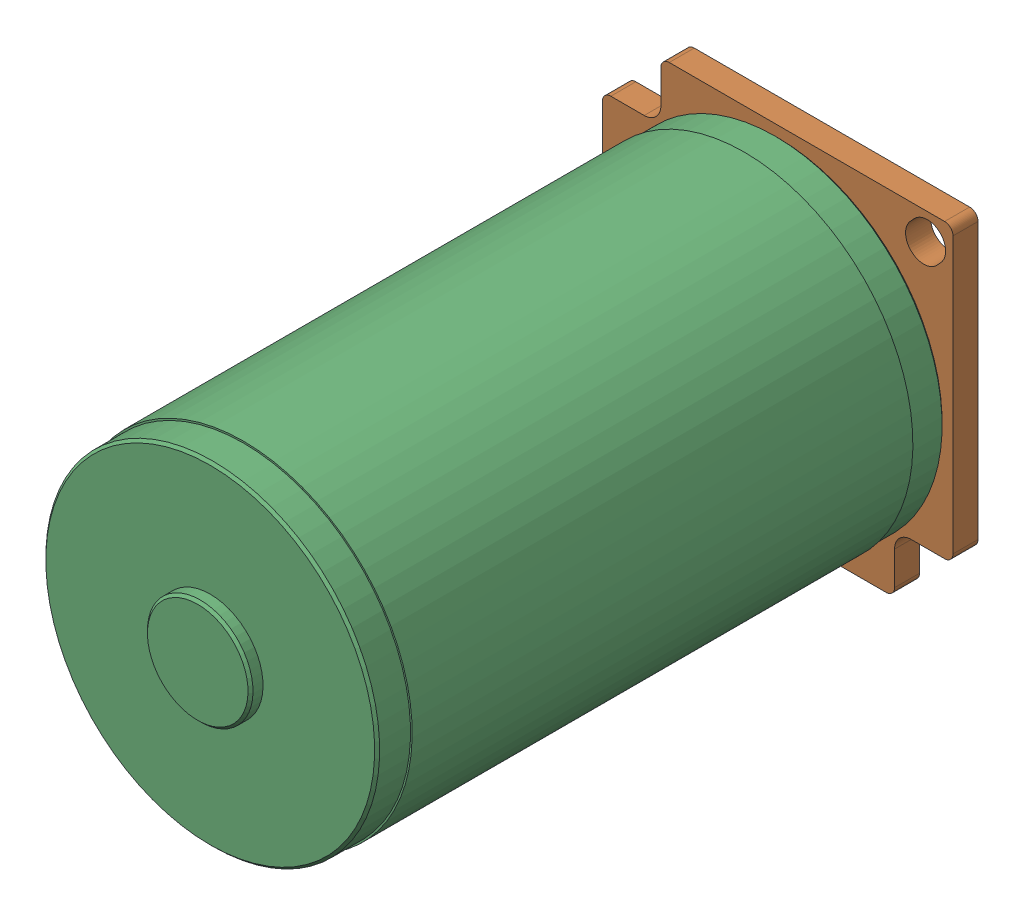
SolidWorks assembly 217-3564-000 Rev1_BAG, configuration Default. Lengths in mm.
Overall size (42 42 81.5).
3 component instances, 3 part files, 0 mates.
Components (placement in the parent):
- 217-2625-011 Rev1-1: 217-2625-011 Rev1 [Default] at (0 0 -5.25) x (1 0 0) z (0 -1 0) size (8.01 7.5 7.94)
- 217-2822-003 Rev4-1: 217-2822-003 Rev4 [Default] at (0 0 1.5) size (42 42 4.8)
- 217-3351-1: 217-3351 [Default] at (0 0 3) x (0 1 0) z (0 0 -1) size (40.4 40.4 81.5)
